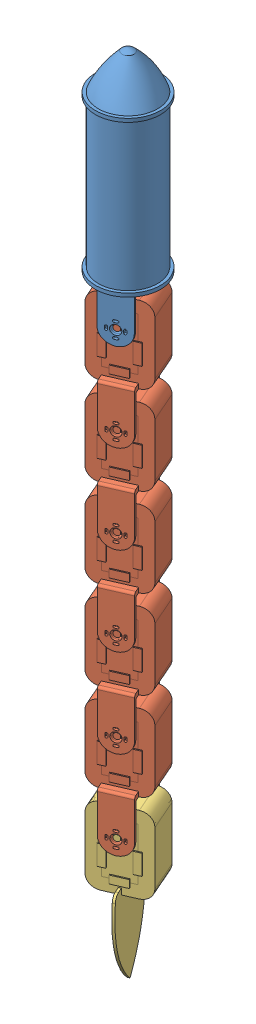
SolidWorks assembly short_tail_eel, configuration 預設. Lengths in mm.
Overall size (61.09 681.18 63.51).
7 component instances, 3 part files, 19 mates.
Components (placement in the parent):
- base_link-1: base_link [預設] at (-66.5632 -1.1579 104.9753) size (55 204.98 55)
- link2-1: link2 [預設] at (-45.8446 -161.6209 204.2877) x (0 1 0) z (0.399282 0 0.916828) size (107 45 40.5)
- link2-2: link2 [預設] at (-45.8446 -236.3209 204.2877) x (0 1 0) z (0.399282 0 0.916828) size (107 45 40.5)
- link2-3: link2 [預設] at (-45.8446 -311.0209 204.2877) x (0 1 0) z (0.399282 0 0.916828) size (107 45 40.5)
- link2-4: link2 [預設] at (-45.8446 -385.7209 204.2877) x (0 1 0) z (0.399282 0 0.916828) size (107 45 40.5)
- link2-5: link2 [預設] at (-45.8446 -460.4209 204.2877) x (0 1 0) z (0.399282 0 0.916828) size (107 45 40.5)
- short_eel-1: short_eel [預設] at (-104.79 -493.4836 67.4418) x (0 1 0) z (0.399282 0 0.916828) size (135 45 49.68)
Mates (geometry in assembly coordinates):
- 同軸心1: concentric aligned: cylinder of base_link-1 through (-52.4327 -86.9209 189.16) axis (-0.399282 0 -0.916828) radius 2.7; cylinder of link2-1 through (-51.4345 -86.9209 191.4521) axis (-0.399282 0 -0.916828) radius 2.5
- 平行1: parallel aligned: plane of base_link-1 through (-42.6286 -56.9209 181.6182) normal (0.916828 0 -0.399282); plane of link2-1 through (-19.626 -131.6209 208.1394) normal (0.916828 0 -0.399282)
- 重合/共線/共點1: coincident aligned: circle of base_link-1; plane of link2-1 through (-38.2582 -86.9209 221.7074) normal (0.399282 0 0.916828)
- 重合/共線/共點2: coincident aligned: plane of link2-1 through (-60.8832 -131.6209 226.1071) normal (-0.916828 0 0.399282); plane of link2-2 through (-60.8832 -206.3209 226.1071) normal (-0.916828 0 0.399282)
- 同軸心2: concentric anti-aligned: cylinder of link2-1 through (-53.8302 -161.6209 185.9511) axis (0.399282 0 0.916828) radius 3.7; cylinder of link2-2 through (-51.4345 -161.6209 191.4521) axis (-0.399282 0 -0.916828) radius 2.5
- 平行2: parallel aligned: plane of link2-1 through (-54.7929 -154.5209 186.3704) normal (0 -1 0); plane of link2-2 through (-54.7929 -229.2209 186.3704) normal (0 -1 0)
- 重合/共線/共點4: coincident aligned: plane of link2-1 through (-51.4345 -71.6862 191.4521) normal (-0.399282 0 -0.916828); plane of link2-2 through (-51.4345 -146.3862 191.4521) normal (-0.399282 0 -0.916828)
- 重合/共線/共點5: coincident aligned: plane of link2-2 through (-60.8832 -206.3209 226.1071) normal (-0.916828 0 0.399282); plane of link2-3 through (-60.8832 -281.0209 226.1071) normal (-0.916828 0 0.399282)
- 同軸心3: concentric anti-aligned: cylinder of link2-2 through (-53.8302 -236.3209 185.9511) axis (0.399282 0 0.916828) radius 3.7; cylinder of link2-3 through (-51.4345 -236.3209 191.4521) axis (-0.399282 0 -0.916828) radius 2.5
- 重合/共線/共點6: coincident aligned: plane of link2-2 through (-53.8302 -146.3862 185.9511) normal (-0.399282 0 -0.916828); plane of link2-3 through (-53.8302 -221.0862 185.9511) normal (-0.399282 0 -0.916828)
- 重合/共線/共點7: coincident aligned: plane of link2-3 through (-60.8832 -281.0209 226.1071) normal (-0.916828 0 0.399282); plane of link2-4 through (-60.8832 -355.7209 226.1071) normal (-0.916828 0 0.399282)
- 同軸心4: concentric anti-aligned: cylinder of link2-3 through (-53.8302 -311.0209 185.9511) axis (0.399282 0 0.916828) radius 3.7; cylinder of link2-4 through (-51.4345 -311.0209 191.4521) axis (-0.399282 0 -0.916828) radius 2.5
- 重合/共線/共點8: coincident aligned: plane of link2-3 through (-51.4345 -221.0862 191.4521) normal (-0.399282 0 -0.916828); plane of link2-4 through (-51.4345 -295.7862 191.4521) normal (-0.399282 0 -0.916828)
- 重合/共線/共點10: coincident aligned: plane of link2-4 through (-51.4345 -295.7862 191.4521) normal (-0.399282 0 -0.916828); plane of link2-5 through (-51.4345 -370.4862 191.4521) normal (-0.399282 0 -0.916828)
- 重合/共線/共點11: coincident aligned: plane of link2-4 through (-60.8832 -355.7209 226.1071) normal (-0.916828 0 0.399282); plane of link2-5 through (-60.8832 -430.4209 226.1071) normal (-0.916828 0 0.399282)
- 同軸心6: concentric anti-aligned: cylinder of link2-4 through (-53.8302 -385.7209 185.9511) axis (0.399282 0 0.916828) radius 3.7; cylinder of link2-5 through (-51.4345 -385.7209 191.4521) axis (-0.399282 0 -0.916828) radius 2.5
- 重合/共線/共點12: coincident aligned: plane of link2-5 through (-60.8832 -430.4209 226.1071) normal (-0.916828 0 0.399282); plane of short_eel-1 through (-60.8832 -505.1209 226.1071) normal (-0.916828 0 0.399282)
- 重合/共線/共點13: coincident aligned: plane of link2-5 through (-51.4345 -370.4862 191.4521) normal (-0.399282 0 -0.916828); plane of short_eel-1 through (-51.4345 -445.1862 191.4521) normal (-0.399282 0 -0.916828)
- 同軸心7: concentric anti-aligned: cylinder of link2-5 through (-53.8302 -460.4209 185.9511) axis (0.399282 0 0.916828) radius 3.7; cylinder of short_eel-1 through (-51.4345 -460.4209 191.4521) axis (-0.399282 0 -0.916828) radius 2.5
